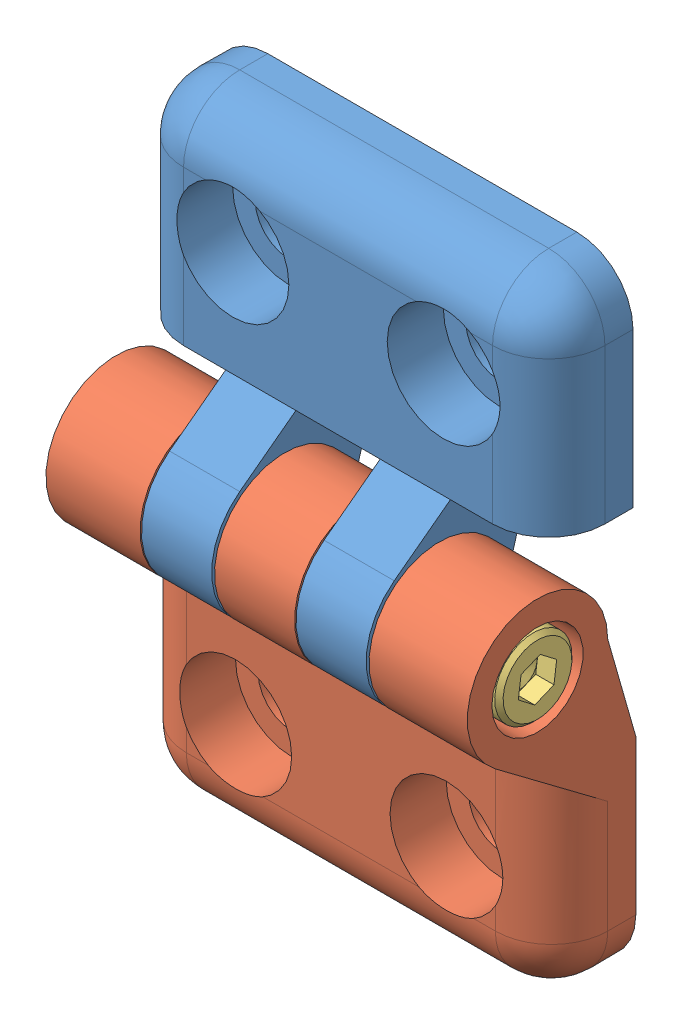
SolidWorks assembly back_door_hinge, configuration Default. Lengths in mm.
Overall size (30.2 44 12).
3 component instances, 3 part files, 6 mates.
Components (placement in the parent):
- hinge_arm-1: hinge_arm [Default] at (-16.615 19.2024 20.3602) size (30 27 12)
- hinge_backdoor_base-1: hinge_backdoor_base [Default] at (13.585 5.2024 20.3602) x (-1 0 0) z (0 0 1) size (30 27 12)
- socket head cap screw_am-2: socket head cap screw_am [B18.3.1M - 3 x 0.5 x 25 Hex SHCS -- 25CHX] at (13.585 12.2024 27.3602) x (-1 0 0) z (0 0.924225 0.381849) size (28 5.5 5.5)
Mates (geometry in assembly coordinates):
- Parallel1: parallel anti-aligned: plane of hinge_arm-1 through (6.385 7.2024 36.4958) normal (1 0 0); plane of hinge_backdoor_base-1 through (-16.415 5.2024 26.3602) normal (-1 0 0)
- Concentric1: concentric anti-aligned: cylinder of hinge_arm-1 through (13.385 12.2024 27.3602) axis (-1 0 0) radius 1.7; cylinder of hinge_backdoor_base-1 through (13.585 12.2024 27.3602) axis (1 0 0) radius 1.8
- Parallel2: parallel aligned: plane of hinge_arm-1 through (-16.615 19.2024 20.3602) normal (0 0 -1); plane of hinge_backdoor_base-1 through (13.585 5.2024 20.3602) normal (0 0 -1)
- Distance1: distance = 0.1 mm anti-aligned: plane of hinge_backdoor_base-1 through (1.285 17.2024 34.0917) normal (1 0 0); plane of hinge_arm-1 through (1.385 7.2024 34.0917) normal (-1 0 0)
- Concentric2: concentric aligned: cylinder of hinge_backdoor_base-1 through (13.585 12.2024 27.3602) axis (1 0 0) radius 1.8; cylinder of socket head cap screw_am-2 through (45.335 12.2024 27.3602) axis (1 0 0) radius 2.75
- Coincident4: coincident anti-aligned: plane of hinge_backdoor_base-1 through (10.585 10.4024 27.3602) normal (1 0 0); plane of socket head cap screw_am-2 through (10.585 11.1523 29.9018) normal (-1 0 0)
